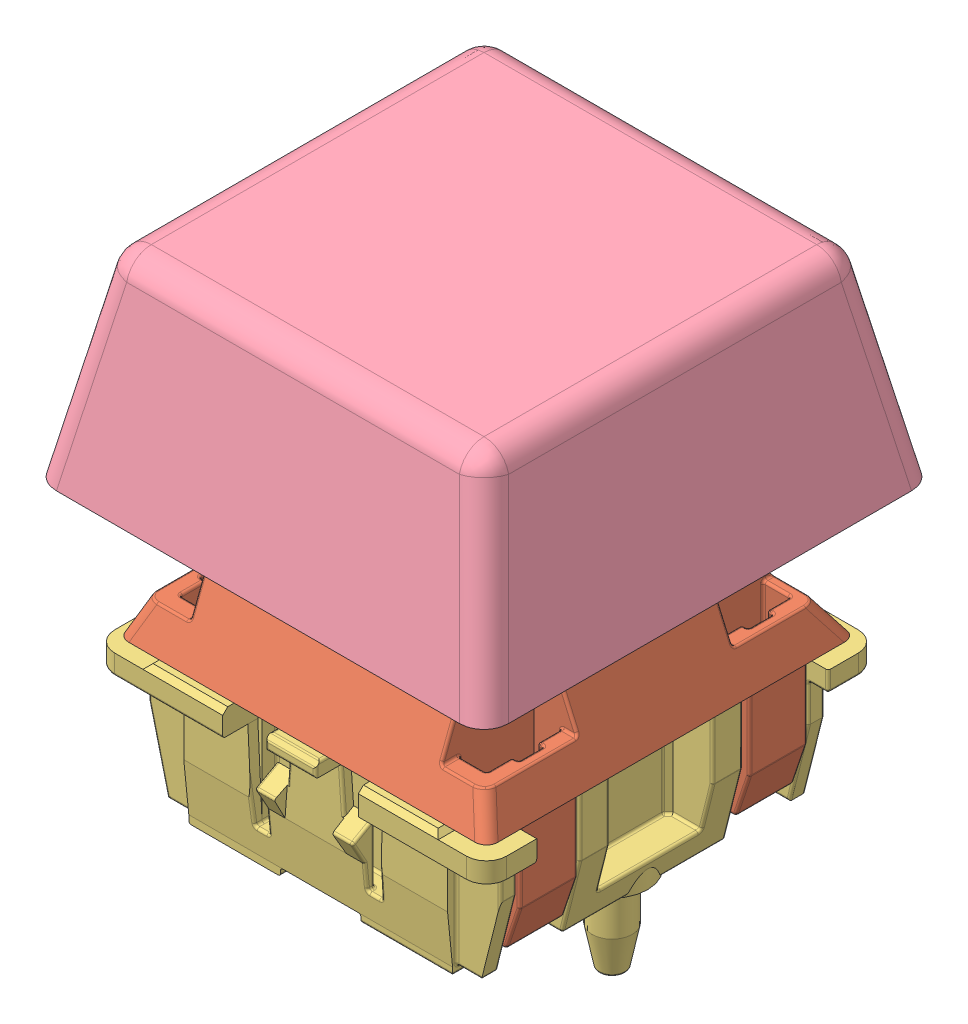
SolidWorks assembly MX, configuration Default. Lengths in mm.
Overall size (18 22.4 18).
6 component instances, 6 part files, 6 mates.
Components (placement in the parent):
- MX _ ___2-1: MX _ ___2 [Default] at (7.35 2 -7.35) size (8.91 10.41 5.71)
- MX _ __-1: MX _ __ [Default] at origin size (14.7 9.91 14.7)
- MX_ __LED-1: MX_ __LED [Default] at (7.35 0.5 -12.292) size (3 15.3 3) (hidden)
- MX_ __ _____-1: MX_ __ _____ [Default] at (7.35 -0.2 -7.35) size (15.6 12.5 15.6)
- Cherry MX Keycap-1: Cherry MX Keycap [Default] at (7.1 6.2 -7.1) x (-0.008727 0 0.999962) z (-0.999962 0 -0.008727) size (18.24 9.84 18.31) (hidden)
- Flat Keycap-1: Flat Keycap [Default] at (7.3192 5.5 -7.2808) size (18 8 18)
Mates (geometry in assembly coordinates):
- Coincident2: coincident anti-aligned: plane of MX _ ___2-1 through (7.35 5.7 -7.35) normal (0 1 0); plane of Cherry MX Keycap-1 through (7.1 5.7 -7.1) normal (0 -1 0)
- Tangent5: tangent aligned: plane of MX _ ___2-1 through (6.8 9.4 -9.35) normal (0 0 -1); cylinder of Cherry MX Keycap-1 through (7.1 14.9726 -7.1) axis (0 -1 0) radius 2.25
- Tangent7: tangent aligned: plane of MX _ ___2-1 through (9.35 9.4 -8) normal (1 0 0); cylinder of Cherry MX Keycap-1 through (7.1 14.9726 -7.1) axis (0 -1 0) radius 2.25
- Coincident3: coincident: plane of MX _ ___2-1 through (7.9 9.4 -5.35) normal (1 0 0); plane of Flat Keycap-1 through (7.9 16.4033 -7.2808) normal (-1 0 0)
- Coincident4: coincident: plane of MX _ ___2-1 through (7.9 9.4 -6.7) normal (0 0 1); plane of Flat Keycap-1 through (7.3192 16.4033 -6.7) normal (0 0 -1)
- Distance2: distance = 19 mm anti-aligned: plane of Flat Keycap-1 through (7.3192 13.5 -7.2808) normal (0 1 0); plane of MX_ __ _____-1 through (7.35 -5.5 -7.35) normal (0 -1 0)
